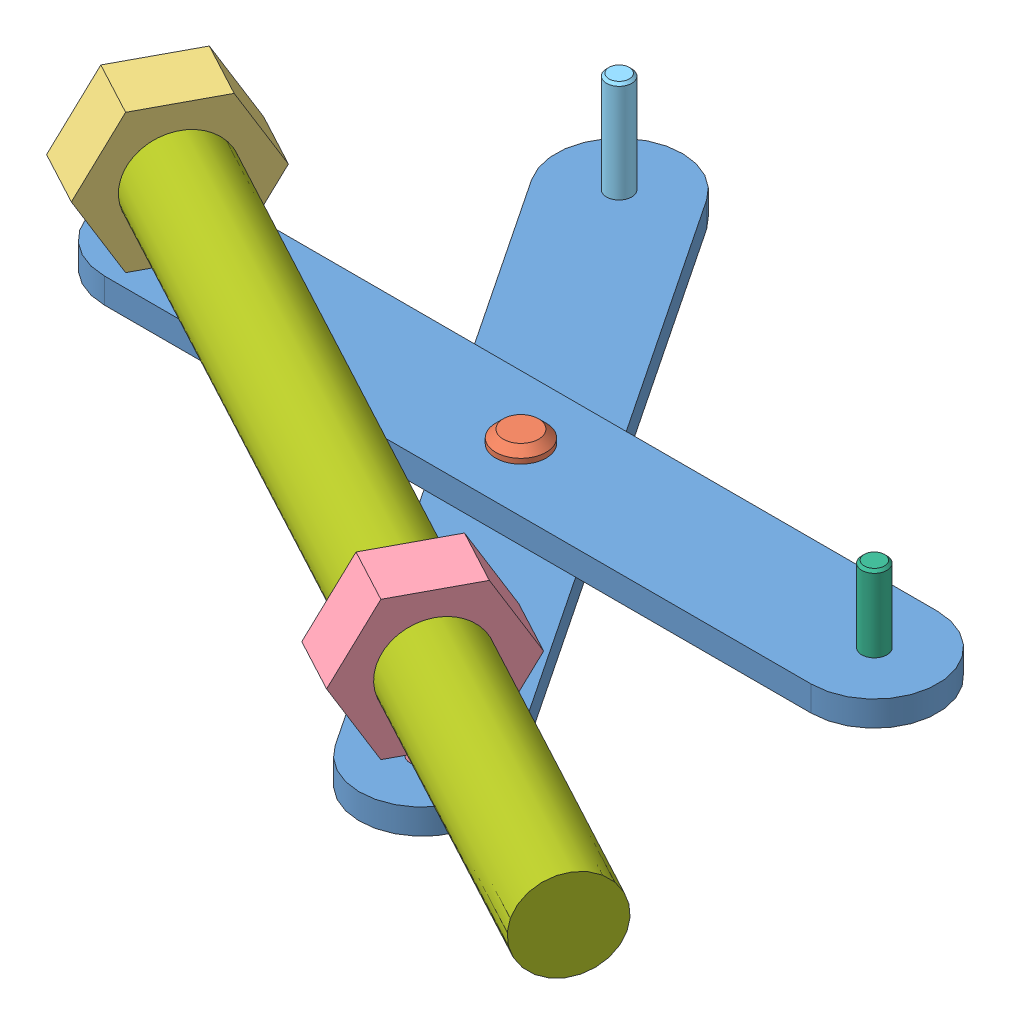
SolidWorks assembly Fork, configuration Default. Lengths in mm.
Overall size (38.31 9.31 35.63).
8 component instances, 7 part files, 9 mates.
Components (placement in the parent):
- Forca-1: Forca [Default] at (-3.8834 29.4971 17.2622) size (33 1 5)
- Hinge-1: Hinge [Default] at (-3.8834 30.2471 17.2622) size (2 2.5 2)
- Hinge_nut_1-1: Hinge_nut_1 [Default] at (-17.8834 32.7471 17.2622) x (-0.236018 0.866025 0.44079) z (-0.408795 -0.5 0.76347) size (6.67 2.4 5.5)
- Hinge_nut_2-1: Hinge_nut_2 [Default] at (-1.856 40.6376 23.1128) x (-0.236018 0.866025 0.44079) z (-0.408795 -0.5 0.76347) size (7.54 2.4 5.56)
- Pin-1: Pin [Default] at (-11.6445 30.4971 5.6104) size (1 5 1)
- Pin_short-1: Pin_short [Default] at (10.1166 30.9971 17.2622) size (1 4 1)
- Rod-1: Rod [Default] at (-1.3097 32.7471 26.1365) x (-0.260996 -0.833237 0.48744) z (0.881579 0 0.472036) size (3.6 3.6 40)
- Forca-2: Forca [Default] at (-3.8834 28.4971 17.2622) x (-0.554364 0 -0.832274) z (0.832274 0 -0.554364) size (33 1 5)
Mates (geometry in assembly coordinates):
- Cardine1: hinge anti-aligned: cylinder of Hinge-1 through (-3.8834 27.9971 17.2622) axis (0 1 0) radius 0.5; cylinder of Forca-1 through (-3.8834 29.9971 17.2622) axis (0 -1 0) radius 0.5; plane of Hinge-1 through (-3.8834 29.9971 17.2622) normal (0 -1 0); plane of Forca-1 through (-17.8834 29.9971 17.2622) normal (0 1 0)
- Coincidente1: coincident anti-aligned: circle of Hinge-1; circle of Forca-2
- Coincidente2: coincident aligned: circle of Pin-1; circle of Forca-2
- Coincidente3: coincident aligned: circle of Forca-1; circle of Pin_short-1
- Cardine2: hinge anti-aligned: cylinder of Hinge_nut_1-1 through (-17.8834 28.9971 17.2622) axis (0 1 0) radius 0.5; cylinder of Forca-1 through (-17.8834 29.9971 17.2622) axis (0 -1 0) radius 0.5; plane of Forca-1 through (-17.8834 29.9971 17.2622) normal (0 1 0); plane of Hinge_nut_1-1 through (-18.1918 29.9971 15.2961) normal (0 -1 0)
- Coincidente4: coincident anti-aligned: circle of Hinge_nut_2-1; circle of Forca-2
- Concentrico1: concentric aligned: cylinder of Hinge_nut_1-1 through (25.1377 32.7471 40.2976) axis (-0.881579 0 -0.472036) radius 1.8; cylinder of Hinge_nut_2-1 through (46.8988 32.7471 51.9494) axis (-0.881579 0 -0.472036) radius 1.8
- Coincidente5: coincident anti-aligned: circle of Hinge_nut_1-1; circle of Rod-1
- Vite1: screw = 1 mm aligned: circle of Hinge_nut_2-1; cylinder of Rod-1 through (16.3219 32.7471 35.5772) axis (-0.881579 0 -0.472036) radius 1.8
